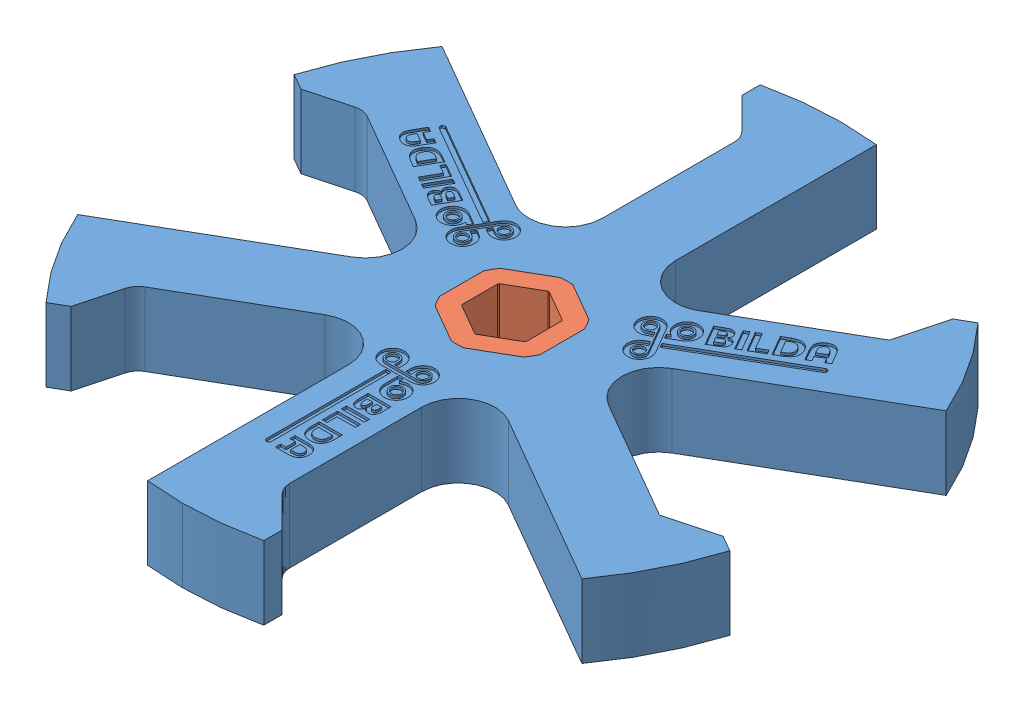
SolidWorks assembly 72mm Boot Wheel 3615-4008-0072, configuration Default. Lengths in mm.
Overall size (68.79 8 72).
2 component instances, 2 part files, 0 mates.
Components (placement in the parent):
- 3615-4008-0072 rubber.STEP-1: 3615-4008-0072 rubber.STEP [Default] at (-40.2734 9.6874 14.6702) size (68.79 8 72)
- 3615-4008-0072 Core.STEP-1: 3615-4008-0072 Core.STEP [Default] at (-40.2734 5.6874 14.6702) x (0.866025 0 -0.5) z (0.5 0 0.866025) size (12 8 11)
